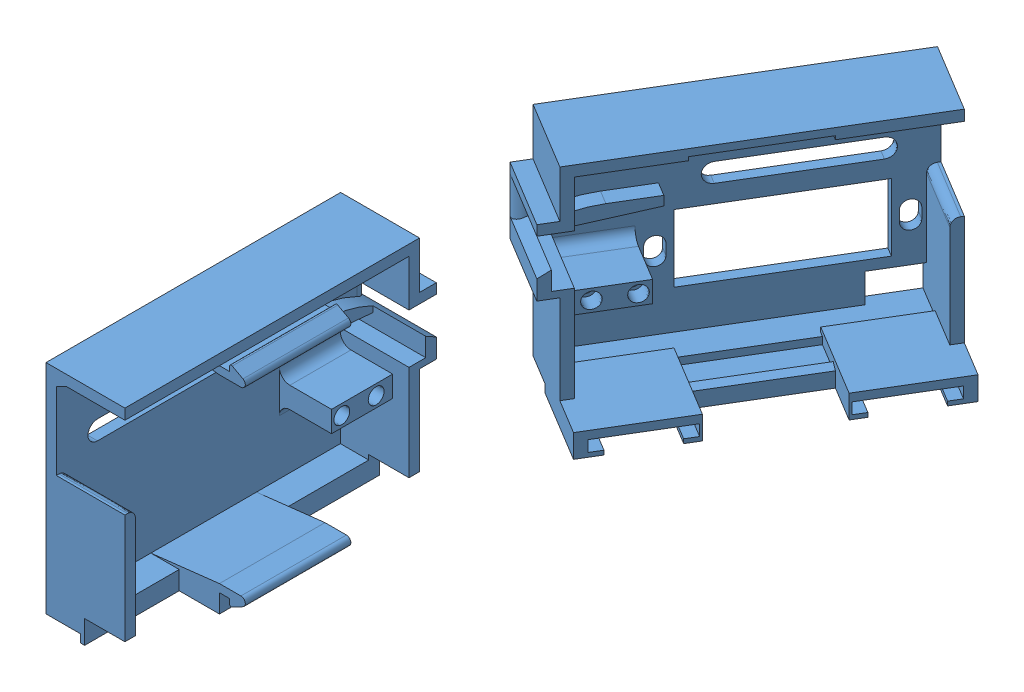
SolidWorks assembly Assem1, configuration Default. Lengths in mm.
Overall size (52.08 42.75 136.38).
2 component instances, 1 part files, 3 mates.
Components (placement in the parent):
- lvrV2_housing1-1: lvrV2_housing1 [LeftSide] at (-76.0549 -0.2217 93.5885) size (19.97 42.75 59)
- lvrV2_housing1-2: lvrV2_housing1 [RightSide] at (-58.153 -0.2217 -46.8) x (0.856285 0 0.516504) z (-0.516504 0 0.856285) size (22.74 42.75 59)
Mates (geometry in assembly coordinates):
- Coincident1: coincident aligned: plane of lvrV2_housing1-1 through (-74.1049 20.4033 93.5885) normal (0 1 0); plane of lvrV2_housing1-2 through (-56.4832 20.4033 -45.7928) normal (0 1 0)
- Coincident2: coincident: plane of lvrV2_housing1-1 through (-76.0549 -0.2217 93.5885) normal (-1 0 0); plane of lvrV2_housing1-2
- Coincident4: coincident: line of lvrV2_housing1-2 through (-61.1049 -1.0767 -12.9615) axis (0 1 0)
